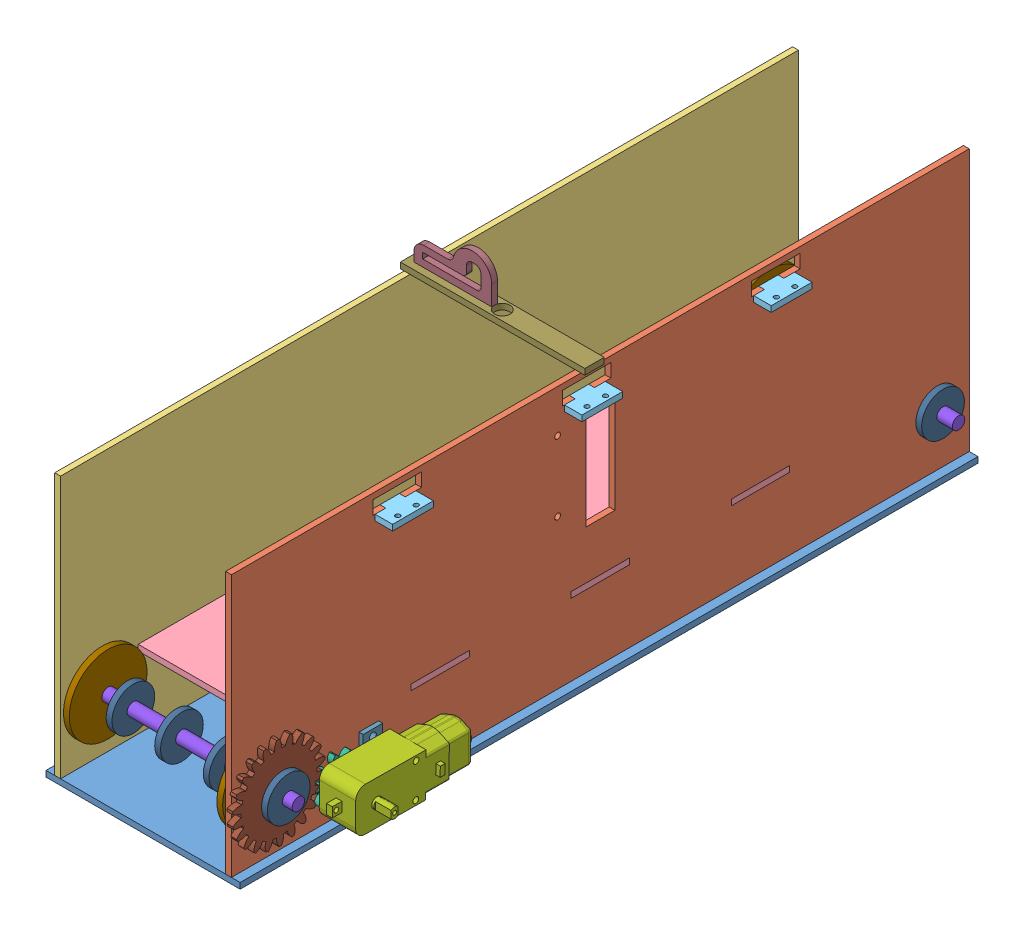
SolidWorks assembly EnsambleBanda, configuration Predeterminado. Lengths in mm.
Overall size (128.87 161.82 399.89).
29 component instances, 14 part files, 66 mates.
Components (placement in the parent):
- BAseGeneral-1: BAseGeneral [Predeterminado] at (-4.2266 -31.7563 350) size (100 3 380)
- ParedDerecha-2: ParedDerecha [Predeterminado] at (38.2734 38.7437 350) x (0 0 -1) z (1 0 0) size (380 138 3)
- ParedIzquierda-1: ParedIzquierda [Predeterminado] at (-46.7266 38.7437 350) x (0 0 1) z (-1 0 0) size (380 138 3)
- base-1: base [Predeterminado] at (-4.2266 8.2437 350) size (91 3 300)
- soporteFinCarrera-1: soporteFinCarrera [Predeterminado] at (38.2734 93.2437 265.5) x (0 0 -1) z (1 0 0) size (21 3 12)
- soporteFinCarrera-2: soporteFinCarrera [Predeterminado] at (38.2734 93.2437 460.5) x (0 0 -1) z (1 0 0) size (21 3 12)
- soporteFinCarrera-3: soporteFinCarrera [Predeterminado] at (38.2734 93.2437 363) x (0 0 -1) z (1 0 0) size (21 3 12)
- MiEngranePequeñoV2-1: MiEngranePequeñoV2 [Predeterminado] at (42.7734 384.4008 222.5284) x (0 -0.999961 0.008878) z (0 0.008878 0.999961) size (23.7 3 23.48)
- Motor-1: Motor [Predeterminado] at (65.5434 -8.5781 489.3215) x (0 -0.008878 -0.999961) z (0 0.999961 -0.008878) size (70.2 36.87 22.3)
- ejeRuedas-1: ejeRuedas [Predeterminado] at (55.7734 1.2437 520) x (0 1 0) z (0 0 1) size (6.4 110 6.4)
- RuedaGrande-1: RuedaGrande [Predeterminado] at (-42.2266 1.2437 520) x (0 1 0) z (0 0 1) size (40 3 40)
- RuedaGrande-2: RuedaGrande [Predeterminado] at (36.7734 1.2437 520) x (0 1 0) z (0 0 1) size (40 3 40)
- ruedaPequeña-1: ruedaPequeña [Predeterminado] at (-29.2266 1.2437 520) x (0 1 0) z (0 0 1) size (22 3 22)
- ruedaPequeña-2: ruedaPequeña [Predeterminado] at (-4.2266 1.2437 520) x (0 1 0) z (0 0 1) size (22 3 22)
- ruedaPequeña-3: ruedaPequeña [Predeterminado] at (20.7734 1.2437 520) x (0 1 0) z (0 0 1) size (22 3 22)
- EngraneGrande-1: EngraneGrande [Predeterminado] at (42.7734 -30.0906 1041.862) x (0 0.673646 -0.739054) z (1 0 0) size (48.01 47.68 3)
- ruedaPequeña-4: ruedaPequeña [Predeterminado] at (47.7734 1.2437 520) x (0 -1 0) z (0 0 1) size (22 3 22)
- ruedaPequeña-5: ruedaPequeña [Predeterminado] at (-53.2266 1.2437 520) x (0 -1 0) z (0 0 1) size (22 3 22)
- ejeRuedas-2: ejeRuedas [Predeterminado] at (55.7734 1.2437 180) x (0 1 0) z (0 0 1) size (6.4 110 6.4)
- ruedaPequeña-6: ruedaPequeña [Predeterminado] at (-50.2266 1.2437 180) x (0 1 0) z (0 0 1) size (22 3 22)
- ruedaPequeña-7: ruedaPequeña [Predeterminado] at (-4.2266 1.2437 180) x (0 1 0) z (0 0 1) size (22 3 22)
- ruedaPequeña-8: ruedaPequeña [Predeterminado] at (20.7734 1.2437 180) x (0 1 0) z (0 0 1) size (22 3 22)
- RuedaGrande-3: RuedaGrande [Predeterminado] at (-41.2266 1.2437 180) x (0 1 0) z (0 0 1) size (40 3 40)
- RuedaGrande-4: RuedaGrande [Predeterminado] at (32.7734 1.2437 180) x (0 -0.381849 0.924225) z (0 0.924225 0.381849) size (40 3 40)
- ruedaPequeña-9: ruedaPequeña [Predeterminado] at (47.7734 1.2437 180) x (0 1 0) z (0 0 1) size (22 3 22)
- ruedaPequeña-10: ruedaPequeña [Predeterminado] at (-29.2266 1.2437 180) x (0 1 0) z (0 0 1) size (22 3 22)
- Travesaño-1: Travesaño [Predeterminado] at (-4.2266 106.2437 355) size (95 3 10)
- GuiaMangera-1: GuiaMangera [Predeterminado] at (-28.1798 119.2437 353.5) size (40 23 3)
- SoporteMotor-1: SoporteMotor [Predeterminado] at (40.445 -8.7563 469.3) x (0 0 -1) z (1 0 0) size (10 24 3)
Mates (geometry in assembly coordinates):
- Coincidente2: coincident anti-aligned: plane of BAseGeneral-1 through (41.2734 -28.7563 417.5) normal (-1 0 0); plane of ParedDerecha-2 through (41.2734 38.7437 350) normal (1 0 0)
- Coincidente4: coincident anti-aligned: plane of BAseGeneral-1 through (38.2734 -28.7563 447.5) normal (0 0 -1); plane of ParedDerecha-2 through (41.2734 38.7437 447.5) normal (0 0 1)
- Coincidente5: coincident aligned: plane of BAseGeneral-1 through (-4.2266 -31.7563 350) normal (0 -1 0); plane of ParedDerecha-2 through (41.2734 -31.7563 350) normal (0 -1 0)
- Coincidente6: coincident anti-aligned: plane of BAseGeneral-1 through (-49.7266 -28.7563 417.5) normal (1 0 0); plane of ParedIzquierda-1 through (-49.7266 38.7437 350) normal (-1 0 0)
- Coincidente7: coincident anti-aligned: plane of BAseGeneral-1 through (-49.7266 -28.7563 447.5) normal (0 0 -1); plane of ParedIzquierda-1 through (-49.7266 -31.7563 447.5) normal (0 0 1)
- Coincidente8: coincident aligned: plane of BAseGeneral-1 through (-4.2266 -31.7563 350) normal (0 -1 0); plane of ParedIzquierda-1 through (-49.7266 -31.7563 335) normal (0 -1 0)
- Coincidente9: coincident aligned: plane of ParedDerecha-2 through (41.2734 38.7437 350) normal (1 0 0); plane of base-1 through (41.2734 11.2437 447.5) normal (1 0 0)
- Coincidente10: coincident anti-aligned: plane of ParedDerecha-2 through (41.2734 38.7437 447.5) normal (0 0 -1); plane of base-1 through (38.2734 11.2437 447.5) normal (0 0 1)
- Coincidente11: coincident anti-aligned: plane of ParedDerecha-2 through (41.2734 11.2437 350) normal (0 -1 0); plane of base-1 through (-4.2266 11.2437 350) normal (0 1 0)
- Coincidente12: coincident anti-aligned: plane of ParedDerecha-2 through (41.2734 93.2437 350) normal (0 1 0); plane of soporteFinCarrera-2 through (38.2734 93.2437 460.5) normal (0 -1 0)
- Coincidente13: coincident anti-aligned: plane of ParedDerecha-2 through (41.2734 38.7437 450.5) normal (0 0 1); plane of soporteFinCarrera-2 through (38.2734 96.2437 450.5) normal (0 0 -1)
- Coincidente14: coincident aligned: plane of ParedDerecha-2 through (38.2734 38.7437 350) normal (-1 0 0); plane of soporteFinCarrera-2 through (38.2734 96.2437 460.5) normal (-1 0 0)
- Coincidente15: coincident anti-aligned: plane of ParedDerecha-2 through (41.2734 93.2437 350) normal (0 1 0); plane of soporteFinCarrera-3 through (38.2734 93.2437 363) normal (0 -1 0)
- Coincidente16: coincident anti-aligned: plane of ParedDerecha-2 through (41.2734 38.7437 353) normal (0 0 1); plane of soporteFinCarrera-3 through (38.2734 96.2437 353) normal (0 0 -1)
- Coincidente17: coincident aligned: plane of ParedDerecha-2 through (38.2734 38.7437 350) normal (-1 0 0); plane of soporteFinCarrera-3 through (38.2734 96.2437 363) normal (-1 0 0)
- Coincidente18: coincident anti-aligned: plane of ParedDerecha-2 through (41.2734 93.2437 350) normal (0 1 0); plane of soporteFinCarrera-1 through (38.2734 93.2437 265.5) normal (0 -1 0)
- Coincidente19: coincident anti-aligned: plane of ParedDerecha-2 through (41.2734 38.7437 255.5) normal (0 0 1); plane of soporteFinCarrera-1 through (38.2734 96.2437 255.5) normal (0 0 -1)
- Coincidente20: coincident aligned: plane of ParedDerecha-2 through (38.2734 38.7437 350) normal (-1 0 0); plane of soporteFinCarrera-1 through (38.2734 96.2437 265.5) normal (-1 0 0)
- Coincidente23: coincident anti-aligned: plane of MiEngranePequeñoV2-1 through (45.7734 386.7548 487.6616) normal (0 -0.008878 -0.999961); plane of Motor-1 through (45.7734 -8.5617 491.1715) normal (0 0.008878 0.999961)
- Coincidente24: coincident anti-aligned: plane of MiEngranePequeñoV2-1 through (45.7734 384.4008 222.5284) normal (1 0 0); plane of Motor-1 through (45.7734 -8.5781 489.3215) normal (-1 0 0)
- Coincidente26: coincident aligned: line of MiEngranePequeñoV2-1 through (45.7734 -10.4938 491.1886) axis (-1 0 0); line of Motor-1 through (45.7734 -10.4938 491.1886) axis (-1 0 0)
- Coincidente27: coincident anti-aligned: cylinder of ejeRuedas-1 through (-54.2266 1.2437 520) axis (1 0 0) radius 3.2; circle of RuedaGrande-1
- Concéntrica7: concentric aligned: cylinder of ejeRuedas-1 through (-54.2266 1.2437 520) axis (1 0 0) radius 3.2; cylinder of RuedaGrande-2 through (33.7734 1.2437 520) axis (1 0 0) radius 3.2
- Distancia2: distance = 9 mm aligned: plane of RuedaGrande-1 through (-45.2266 1.2437 520) normal (-1 0 0); plane of ejeRuedas-1 through (-54.2266 1.2437 520) normal (-1 0 0)
- Distancia3: distance = 19 mm aligned: plane of RuedaGrande-2 through (36.7734 1.2437 520) normal (1 0 0); plane of ejeRuedas-1 through (55.7734 1.2437 520) normal (1 0 0)
- Concéntrica8: concentric aligned: cylinder of ejeRuedas-1 through (-54.2266 1.2437 520) axis (1 0 0) radius 3.2; cylinder of ruedaPequeña-1 through (-32.2266 1.2437 520) axis (1 0 0) radius 3.2
- Distancia4: distance = 85 mm aligned: plane of ruedaPequeña-1 through (-29.2266 1.2437 520) normal (1 0 0); plane of ejeRuedas-1 through (55.7734 1.2437 520) normal (1 0 0)
- Concéntrica9: concentric aligned: cylinder of ejeRuedas-1 through (-54.2266 1.2437 520) axis (1 0 0) radius 3.2; cylinder of ruedaPequeña-2 through (-7.2266 1.2437 520) axis (1 0 0) radius 3.2
- Distancia5: distance = 60 mm aligned: plane of ruedaPequeña-2 through (-4.2266 1.2437 520) normal (1 0 0); plane of ejeRuedas-1 through (55.7734 1.2437 520) normal (1 0 0)
- Concéntrica10: concentric aligned: cylinder of ejeRuedas-1 through (-54.2266 1.2437 520) axis (1 0 0) radius 3.2; cylinder of ruedaPequeña-3 through (17.7734 1.2437 520) axis (1 0 0) radius 3.2
- Distancia6: distance = 35 mm aligned: plane of ruedaPequeña-3 through (20.7734 1.2437 520) normal (1 0 0); plane of ejeRuedas-1 through (55.7734 1.2437 520) normal (1 0 0)
- Concéntrica11: concentric anti-aligned: cylinder of ParedDerecha-2 through (41.2734 1.2437 520) axis (-1 0 0) radius 3.5; cylinder of ejeRuedas-1 through (-54.2266 1.2437 520) axis (1 0 0) radius 3.2
- Tangente3: tangent anti-aligned: cylinder of ejeRuedas-1 through (-54.2266 1.2437 520) axis (1 0 0) radius 3.2; face of EngraneGrande-1
- Distancia7: distance = 10 mm aligned: plane of ejeRuedas-1 through (55.7734 1.2437 520) normal (1 0 0); plane of EngraneGrande-1 through (45.7734 -20.0408 514.8334) normal (1 0 0)
- Coincidente38: coincident aligned: plane of MiEngranePequeñoV2-1 through (45.7734 384.4008 222.5284) normal (1 0 0); plane of EngraneGrande-1 through (45.7734 -20.0408 514.8334) normal (1 0 0)
- Concéntrica12: concentric aligned: cylinder of ParedDerecha-2 through (41.2734 -17.5063 469.3) axis (-1 0 0) radius 2; cylinder of Motor-1 through (74.6434 -17.5063 469.3) axis (-1 0 0) radius 1.5
- Paralelo3: parallel aligned: cylinder of ParedDerecha-2 through (41.2734 -0.0063 469.3) axis (-1 0 0) radius 2; cylinder of Motor-1 through (74.6434 -0.0069 469.1446) axis (-1 0 0) radius 1.5
- Coincidente39: coincident aligned: plane of BAseGeneral-1 through (-54.2266 -28.7563 540) normal (-1 0 0); plane of ejeRuedas-1 through (-54.2266 1.2437 520) normal (-1 0 0)
- Concéntrica14: concentric anti-aligned: cylinder of ejeRuedas-1 through (-54.2266 1.2437 520) axis (1 0 0) radius 3.2; cylinder of ruedaPequeña-4 through (50.7734 1.2437 520) axis (-1 0 0) radius 3.2
- Distancia8: distance = 5 mm aligned: plane of ruedaPequeña-4 through (50.7734 1.2437 520) normal (1 0 0); plane of ejeRuedas-1 through (55.7734 1.2437 520) normal (1 0 0)
- Concéntrica16: concentric anti-aligned: cylinder of ejeRuedas-1 through (-54.2266 1.2437 520) axis (1 0 0) radius 3.2; cylinder of ruedaPequeña-5 through (-50.2266 1.2437 520) axis (-1 0 0) radius 3.2
- Distancia9: distance = 1 mm aligned: plane of ruedaPequeña-5 through (-53.2266 1.2437 520) normal (-1 0 0); plane of ejeRuedas-1 through (-54.2266 1.2437 520) normal (-1 0 0)
- Concéntrica17: concentric aligned: cylinder of ejeRuedas-2 through (-54.2266 1.2437 180) axis (1 0 0) radius 3.2; cylinder of ruedaPequeña-10 through (-32.2266 1.2437 180) axis (1 0 0) radius 3.2
- Concéntrica18: concentric anti-aligned: cylinder of ejeRuedas-2 through (-54.2266 1.2437 180) axis (1 0 0) radius 3.2; cylinder of RuedaGrande-4 through (35.7734 1.2437 180) axis (-1 0 0) radius 3.2
- Coincidente42: coincident anti-aligned: cylinder of ejeRuedas-2 through (-54.2266 1.2437 180) axis (1 0 0) radius 3.2; circle of ruedaPequeña-8
- Concéntrica19: concentric aligned: cylinder of ejeRuedas-2 through (-54.2266 1.2437 180) axis (1 0 0) radius 3.2; cylinder of ruedaPequeña-7 through (-7.2266 1.2437 180) axis (1 0 0) radius 3.2
- Concéntrica20: concentric aligned: cylinder of ejeRuedas-2 through (-54.2266 1.2437 180) axis (1 0 0) radius 3.2; cylinder of ruedaPequeña-6 through (-53.2266 1.2437 180) axis (1 0 0) radius 3.2
- Concéntrica21: concentric aligned: cylinder of ejeRuedas-2 through (-54.2266 1.2437 180) axis (1 0 0) radius 3.2; cylinder of RuedaGrande-3 through (-44.2266 1.2437 180) axis (1 0 0) radius 3.2
- Concéntrica22: concentric aligned: cylinder of ejeRuedas-2 through (-54.2266 1.2437 180) axis (1 0 0) radius 3.2; cylinder of ruedaPequeña-9 through (44.7734 1.2437 180) axis (1 0 0) radius 3.2
- Concéntrica23: concentric anti-aligned: circle of ParedIzquierda-1; cylinder of ejeRuedas-2 through (-54.2266 1.2437 180) axis (1 0 0) radius 3.2
- Coincidente43: coincident aligned: plane of BAseGeneral-1 through (-54.2266 -28.7563 540) normal (-1 0 0); plane of ejeRuedas-2 through (-54.2266 1.2437 180) normal (-1 0 0)
- Distancia10: distance = 97 mm aligned: plane of RuedaGrande-3 through (-41.2266 1.2437 180) normal (1 0 0); plane of ejeRuedas-2 through (55.7734 1.2437 180) normal (1 0 0)
- Distancia11: distance = 23 mm anti-aligned: plane of ejeRuedas-2 through (55.7734 1.2437 180) normal (1 0 0); plane of RuedaGrande-4 through (32.7734 1.2437 180) normal (-1 0 0)
- Distancia12: distance = 106 mm aligned: plane of ruedaPequeña-6 through (-50.2266 1.2437 180) normal (1 0 0); plane of ejeRuedas-2 through (55.7734 1.2437 180) normal (1 0 0)
- Distancia13: distance = 35 mm aligned: plane of ruedaPequeña-8 through (20.7734 1.2437 180) normal (1 0 0); plane of ejeRuedas-2 through (55.7734 1.2437 180) normal (1 0 0)
- Distancia14: distance = 60 mm aligned: plane of ruedaPequeña-7 through (-4.2266 1.2437 180) normal (1 0 0); plane of ejeRuedas-2 through (55.7734 1.2437 180) normal (1 0 0)
- Distancia15: distance = 85 mm aligned: plane of ruedaPequeña-10 through (-29.2266 1.2437 180) normal (1 0 0); plane of ejeRuedas-2 through (55.7734 1.2437 180) normal (1 0 0)
- Distancia16: distance = 8 mm aligned: plane of ruedaPequeña-9 through (47.7734 1.2437 180) normal (1 0 0); plane of ejeRuedas-2 through (55.7734 1.2437 180) normal (1 0 0)
- Coincidente51: coincident anti-aligned: plane of ParedDerecha-2 through (41.2734 106.2437 350) normal (0 1 0); plane of Travesaño-1 through (-4.2266 106.2437 355) normal (0 -1 0)
- Distancia17: distance = 2 mm aligned: plane of Travesaño-1 through (43.2734 109.2437 360) normal (1 0 0); plane of ParedDerecha-2 through (41.2734 38.7437 350) normal (1 0 0)
- Distancia18: distance = 190 mm aligned: plane of Travesaño-1 through (-51.7266 109.2437 350) normal (0 0 -1); plane of ParedDerecha-2 through (41.2734 38.7437 160) normal (0 0 -1)
- Coincidente54: coincident anti-aligned: plane of Travesaño-1 through (-43.7266 109.2437 356.5) normal (0 0 -1); plane of GuiaMangera-1 through (-18.1798 119.2437 356.5) normal (0 0 1)
- Coincidente55: coincident anti-aligned: plane of Travesaño-1 through (-43.7266 109.2437 356.5) normal (1 0 0); plane of GuiaMangera-1 through (-43.7266 109.2437 356.5) normal (-1 0 0)
- Coincidente56: coincident aligned: plane of Travesaño-1 through (-4.2266 106.2437 355) normal (0 -1 0); plane of GuiaMangera-1 through (-43.7266 106.2437 356.5) normal (0 -1 0)
- Concéntrica24: concentric anti-aligned: cylinder of ParedDerecha-2 through (41.2734 -0.0063 469.3) axis (-1 0 0) radius 2; circle of SoporteMotor-1
- Concéntrica25: concentric aligned: cylinder of ParedDerecha-2 through (41.2734 -17.5063 469.3) axis (-1 0 0) radius 2; cylinder of SoporteMotor-1 through (43.445 -17.5063 469.3) axis (-1 0 0) radius 1.75
